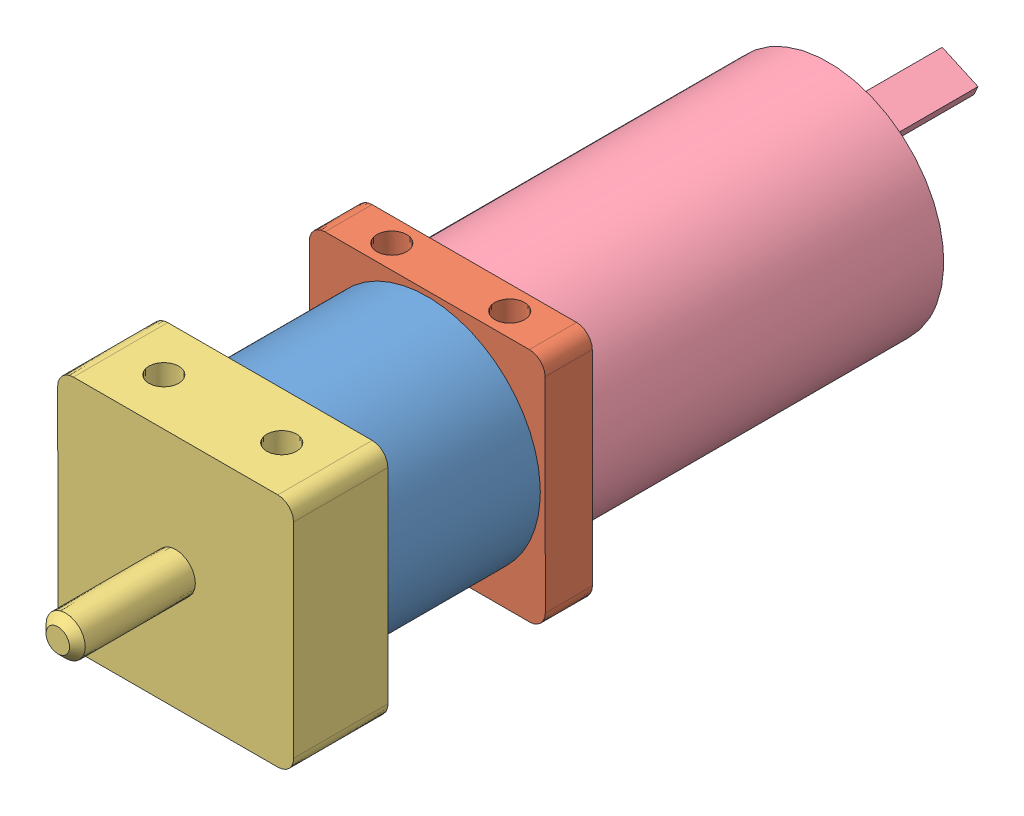
SolidWorks assembly The bamboozler, configuration Default. Lengths in mm.
Overall size (49.42 49.42 132.08).
4 component instances, 4 part files, 8 mates.
Components (placement in the parent):
- Motor Gear thang-1: Motor Gear thang [Default] at (-18.6505 0.7931 -30.0672) size (36.51 36.51 25.4)
- Back thang-1: Back thang [Default] at (-18.6505 0.7931 -37.6872) x (1 0.000908 0) z (0 0 1) size (38.1 38.1 7.62)
- Front thang-2: Front thang [Default] at (-18.6505 0.7931 -4.6672) x (1 0.000908 0) z (0 0 1) size (38.1 38.1 34.29)
- Motor Body-1: Motor Body [Default] at (-18.6505 0.7931 -94.8372) x (0.910927 -0.412569 0) z (0 0 1) size (37.34 37.34 64.77)
Mates (geometry in assembly coordinates):
- Concentric3: concentric: cylinder of Motor Gear thang-1 through (-18.6505 0.7931 -4.6672) axis (0 0 -1) radius 18.2563; cylinder of Back thang-1 through (-18.6505 0.7931 -30.0672) axis (0 0 -1) radius 8.8265
- Coincident3: coincident: plane of Motor Gear thang-1 through (-18.6505 0.7931 -30.0672) normal (0 0 -1); plane of Back thang-1 through (-18.6505 0.7931 -30.0672) normal (0 0 1)
- Concentric4: concentric: circle of Motor Gear thang-1; circle of Front thang-2
- Coincident5: coincident: plane of Motor Gear thang-1 through (-18.6505 0.7931 -4.6672) normal (0 0 1); plane of Front thang-2 through (-18.6505 0.7931 -4.6672) normal (0 0 -1)
- Parallel4: parallel: line of Back thang-1 through (-35.1432 -18.2719 -30.0672) axis (1 0.000908 0); line of Front thang-2 through (-35.1432 -18.2719 -4.6672) axis (1 0.000908 0)
- Concentric6: concentric: circle of Motor Gear thang-1; circle of Back thang-1
- Concentric7: concentric: cylinder of Back thang-1 through (-18.6505 0.7931 -30.0672) axis (0 0 -1) radius 8.8265; cylinder of Motor Body-1 through (-18.6505 0.7931 -37.6872) axis (0 0 -1) radius 18.669
- Coincident7: coincident: plane of Back thang-1 through (-18.6505 0.7931 -37.6872) normal (0 0 -1); plane of Motor Body-1 through (-18.6505 0.7931 -37.6872) normal (0 0 1)
